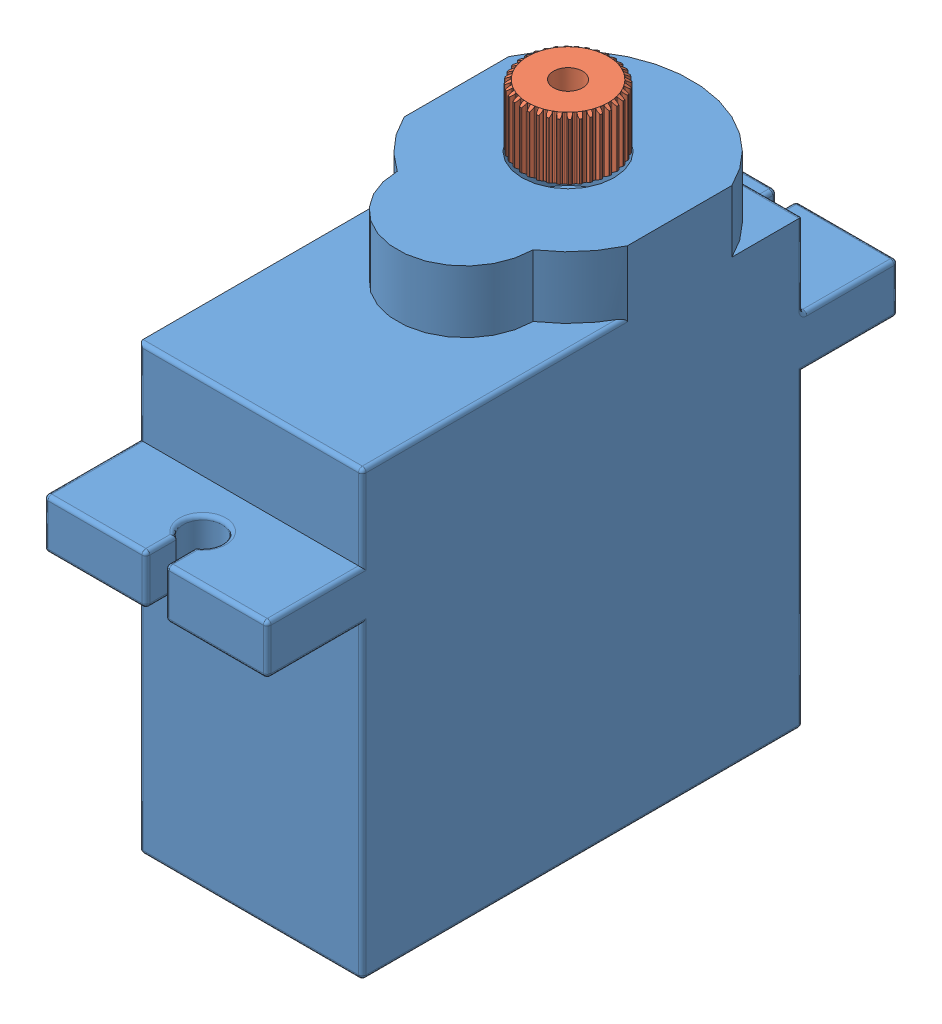
SolidWorks assembly Servo motor, configuration Default. Lengths in mm.
2 component instances, 2 part files, 2 mates.
Components (placement in the parent):
- TowerPro-SG90-Body-1: TowerPro-SG90-Body [Default] at (13.6721 7.288 30.7048) size (11.5 26 32.5)
- ServoFinalGear-1: ServoFinalGear [Default] at (13.6721 33.288 25.7048) x (-0.199292 0 -0.97994) z (0.97994 0 -0.199292) size (4.64 3.2 4.64)
Mates (geometry in assembly coordinates):
- Concentric1: concentric: circle of ServoFinalGear-1; cylinder of TowerPro-SG90-Body-1 through (13.6721 23.3705 25.7048) axis (0 1 0) radius 2.375
- Coincident1: coincident: plane of TowerPro-SG90-Body-1 through (13.6721 33.288 28.354) normal (0 1 0); plane of ServoFinalGear-1 through (13.3414 33.288 23.5891) normal (0 -1 0)
